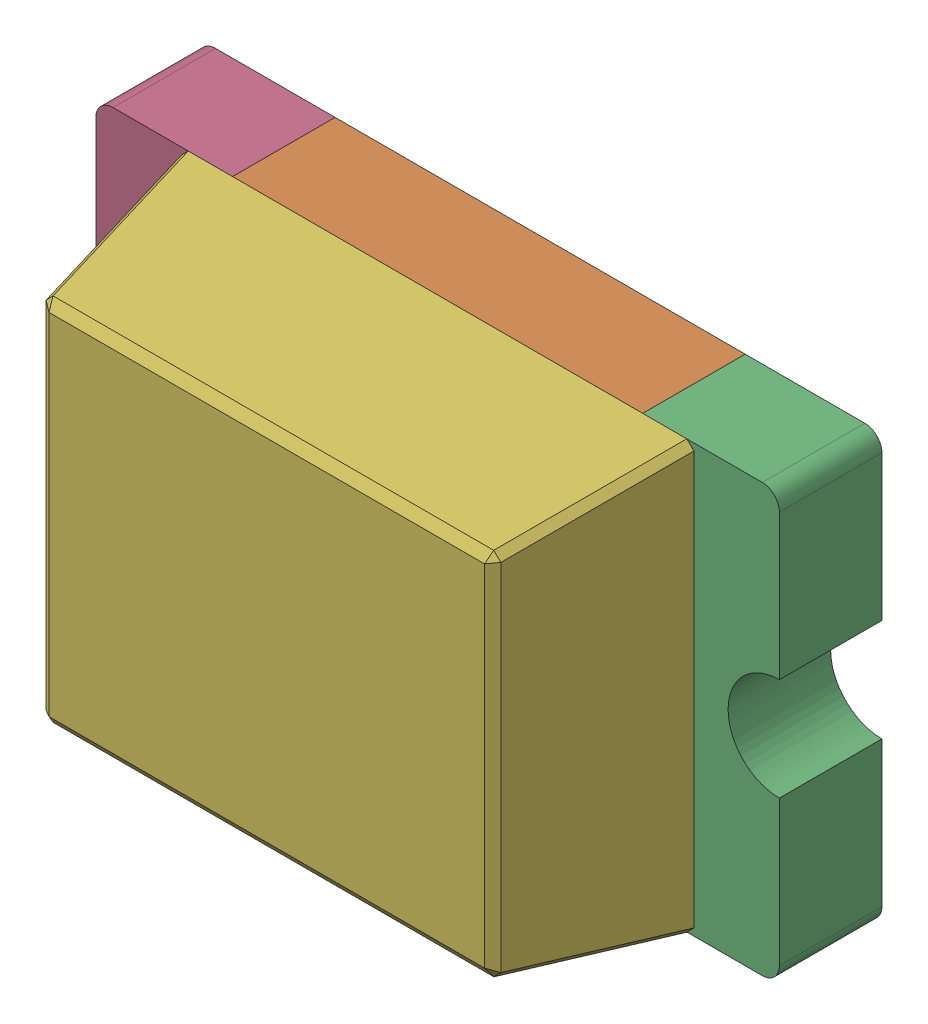
SolidWorks assembly Q9, configuration Standard. Lengths in mm.
Overall size (2 1.25 0.8).
7 component instances, 6 part files, 0 mates.
Components (placement in the parent):
- Q9-subassembly-1-1: Q9-subassembly-1 [Standard] at (-7.1 -3.4999 0) x (1 0 0) z (0 -1 0) size (2 0.8 1.25)
  - 0805 Chip SMD LED (2x1.2mm)-1: 0805 Chip SMD LED (2x1.2mm) [Standard] at origin size (0.2 0.01 0.25)
  - 0805 Chip SMD LED (2x1.2mm)-1-1: 0805 Chip SMD LED (2x1.2mm)-1 [Standard] at origin size (1.96 0.45 1.25)
  - 0805 Chip SMD LED (2x1.2mm)-2-1: 0805 Chip SMD LED (2x1.2mm)-2 [Standard] at origin size (0.4 0.3 1.25)
  - 0805 Chip SMD LED (2x1.2mm)-3-1: 0805 Chip SMD LED (2x1.2mm)-3 [Standard] at origin size (0.4 0.3 1.25)
  - 0805 Chip SMD LED (2x1.2mm)-4-1: 0805 Chip SMD LED (2x1.2mm)-4 [Standard] at origin size (0.2 0.01 0.25)
  - 0805 Chip SMD LED (2x1.2mm)-5-1: 0805 Chip SMD LED (2x1.2mm)-5 [Standard] at origin size (1.5 0.5 1.25)
